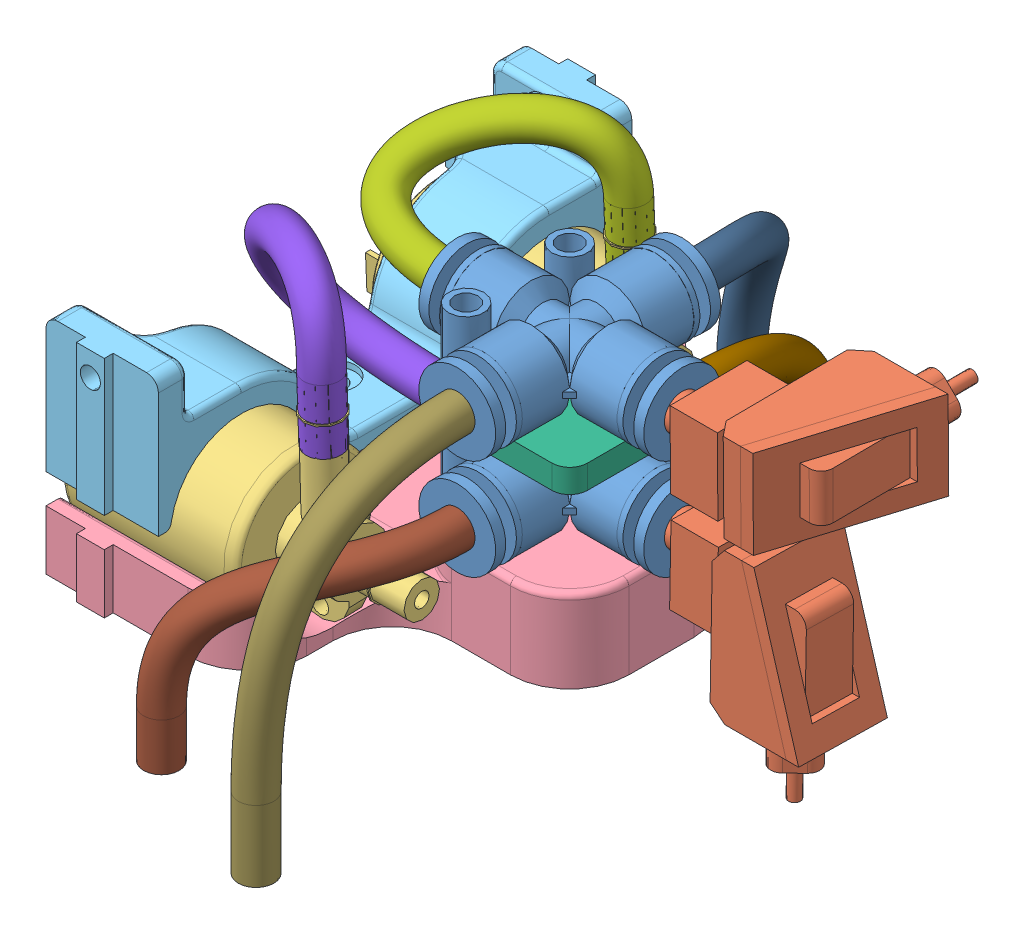
SolidWorks assembly Pneumatique, configuration Défaut. Lengths in mm.
Overall size (98.5 73.06 104.94).
15 component instances, 12 part files, 50 mates.
Components (placement in the parent):
- CroixPiquageRapideD06-1: CroixPiquageRapideD06 [Default] at (39.5 20.5 0) x (0 0 1) z (0 -1 0) size (38 38 13)
- CapteurVide_CKD_PPE-V01A-H6-B-1: CapteurVide_CKD_PPE-V01A-H6-B [Défaut] at (63 20.5 0) x (0 -0.999843 0.017733) z (0 0.017733 0.999843) size (37 43 15)
- Electrovanne_CylindriqueD24_NC_12V-1: Electrovanne_CylindriqueD24_NC_12V [Default] at (-8.5 14 26) x (0 0.999367 0.035582) z (0 0.035582 -0.999367) size (38.24 53 24.48)
- Electrovanne_CylindriqueD24_NC_12V-2: Electrovanne_CylindriqueD24_NC_12V [Default] at (-8.5 14 -26) x (0 0.999176 0.040592) z (0 0.040592 -0.999176) size (38.24 53 24.48)
- CroixPiquageRapideD06-2: CroixPiquageRapideD06 [Default] at (39.5 37.5 0) x (0 0 1) z (0 -1 0) size (38 38 13)
- CapteurVide_CKD_PPE-V01A-H6-B-2: CapteurVide_CKD_PPE-V01A-H6-B [Défaut] at (63 37.5 0) x (0 0.007638 -0.999971) z (0 -0.999971 -0.007638) size (37 43 15)
- Pneumatique_Support-1: Pneumatique_Support [Défaut] at origin size (64.23 14 83)
- Pneumatique_Top-1: Pneumatique_Top [Défaut] at (0 15 0) size (19.23 27.5 83)
- Pneumatique_Entretoise-1: Pneumatique_Entretoise [Défaut] at (39.5 27 0) size (24 4 24)
- tuyau1^Pneumatique-1: tuyau1^Pneumatique [Défaut] at (20.5 37.5 0) x (0 0 1) z (-1 0 0) size (31.4 24.42 35.33) (virtual)
- tuyau2^Pneumatique-1: tuyau2^Pneumatique [Défaut] at (20.5 20.5 0) x (0 0 1) z (-1 0 0) size (33.54 37.08 42) (virtual)
- tuyau3^Pneumatique-1: tuyau3^Pneumatique [Défaut] at (39.5 20.5 -19) x (0 -1 0) z (0 0 -1) size (42.15 12.06 47.59) (virtual)
- tuyau4^Pneumatique-1: tuyau4^Pneumatique [Défaut] at (39.5 37.5 -19) x (0 -1 0) z (0 0 -1) size (49.1 26.51 49.11) (virtual)
- tuyau5^Pneumatique-1: tuyau5^Pneumatique [Défaut] at (39.5 20.5 19) x (0 1 0) z (0 0 1) size (32.28 26.54 48.84) (virtual)
- tuyau6^Pneumatique-1: tuyau6^Pneumatique [Défaut] at (39.5 37.5 19) x (0 1 0) z (0 0 1) size (59 12.1 47.35) (virtual)
Mates (geometry in assembly coordinates):
- Coïncidente420: coincident: plane of assembly; plane of assembly; plane of CroixPiquageRapideD06-1 through (30.75 14 -8.75) normal (0 -1 0); plane of Pneumatique_Support-1 through (0 14 0) normal (0 1 0)
- Coaxiale167: concentric: cylinder of assembly; cylinder of assembly; cylinder of CroixPiquageRapideD06-1 through (30.75 14 -8.75) axis (0 1 0) radius 2; cylinder of Pneumatique_Support-1 through (30.75 14 -8.75) axis (0 1 0) radius 1.7
- Coaxiale168: concentric: cylinder of assembly; cylinder of assembly; cylinder of CroixPiquageRapideD06-1 through (30.75 14 8.75) axis (0 1 0) radius 3; cylinder of Pneumatique_Support-1 through (30.75 14 8.75) axis (0 1 0) radius 1.7
- Coaxiale169: concentric: cylinder of assembly; cylinder of assembly; cylinder of CroixPiquageRapideD06-1 through (30.75 14 -8.75) axis (0 1 0) radius 2; cylinder of CroixPiquageRapideD06-2 through (30.75 31 -8.75) axis (0 1 0) radius 2
- Coaxiale170: concentric: cylinder of assembly; cylinder of assembly; cylinder of CroixPiquageRapideD06-1 through (30.75 14 8.75) axis (0 1 0) radius 2; cylinder of CroixPiquageRapideD06-2 through (30.75 31 8.75) axis (0 1 0) radius 2
- Distance58: distance = 17 mm: plane of assembly; plane of assembly; plane of CroixPiquageRapideD06-2 through (30.75 44 -8.75) normal (0 1 0); plane of CroixPiquageRapideD06-1 through (30.75 27 -8.75) normal (0 1 0)
- Coaxiale171: concentric: cylinder of assembly; cylinder of assembly; cylinder of CroixPiquageRapideD06-1 through (39.5 20.5 0) axis (-1 0 0) radius 3; cylinder of CapteurVide_CKD_PPE-V01A-H6-B-1 through (43 20.5 0) axis (1 0 0) radius 3
- Coïncidente422: coincident: plane of assembly; plane of assembly; plane of CroixPiquageRapideD06-1 through (43 20.5 1.5) normal (1 0 0); plane of CapteurVide_CKD_PPE-V01A-H6-B-1 through (43 20.5 0) normal (-1 0 0)
- Coaxiale174: concentric: cylinder of assembly; cylinder of assembly; cylinder of CroixPiquageRapideD06-1 through (30.75 14 -8.75) axis (0 1 0) radius 2; cylinder of Pneumatique_Entretoise-1 through (30.75 31 -8.75) axis (0 1 0) radius 1.7
- Coaxiale175: concentric: cylinder of assembly; cylinder of assembly; cylinder of CroixPiquageRapideD06-1 through (30.75 14 8.75) axis (0 1 0) radius 3; cylinder of Pneumatique_Entretoise-1 through (30.75 31 8.75) axis (0 1 0) radius 1.7
- Coïncidente426: coincident: plane of assembly; plane of assembly; plane of CroixPiquageRapideD06-1 through (30.75 27 -8.75) normal (0 1 0); plane of Pneumatique_Entretoise-1 through (39.5 27 0) normal (0 -1 0)
- Coïncidente419: coincident: plane of assembly; plane of assembly; plane of Pneumatique_Support-1 through (-9 10 -40) normal (-1 0 0); plane of Electrovanne_CylindriqueD24_NC_12V-1 through (-9 14 26) normal (-1 0 0)
- Coaxiale166: concentric: cylinder of assembly; cylinder of assembly; cylinder of Electrovanne_CylindriqueD24_NC_12V-1 through (-8.5 14 26) axis (1 0 0) radius 12; cylinder of Pneumatique_Support-1 through (58.9411 14 26) axis (-1 0 0) radius 12
- Coïncidente418: coincident: plane of assembly; plane of assembly; plane of Pneumatique_Support-1 through (-9 10 -40) normal (-1 0 0); plane of Electrovanne_CylindriqueD24_NC_12V-2 through (-9 14 -26) normal (-1 0 0)
- Coaxiale165: concentric: cylinder of assembly; cylinder of assembly; cylinder of Electrovanne_CylindriqueD24_NC_12V-2 through (-8.5 14 -26) axis (1 0 0) radius 12; cylinder of Pneumatique_Support-1 through (58.9411 14 -26) axis (-1 0 0) radius 12
- Coaxiale173: concentric: cylinder of assembly; cylinder of assembly; cylinder of Electrovanne_CylindriqueD24_NC_12V-2 through (-8.5 14 -26) axis (1 0 0) radius 12; cylinder of Pneumatique_Top-1 through (43.9411 14 -26) axis (-1 0 0) radius 12
- Coïncidente423: coincident: plane of assembly; plane of assembly; plane of CroixPiquageRapideD06-2 through (43 37.5 1.5) normal (1 0 0); plane of CapteurVide_CKD_PPE-V01A-H6-B-2 through (43 37.5 0) normal (-1 0 0)
- Coaxiale172: concentric: cylinder of CroixPiquageRapideD06-2 through (39.5 37.5 0) axis (-1 0 0) radius 3; cylinder of CapteurVide_CKD_PPE-V01A-H6-B-2 through (43 37.5 0) axis (1 0 0) radius 3
- Coïncidente425: coincident: plane of Pneumatique_Support-1 through (-9 10 -40) normal (-1 0 0); plane of Pneumatique_Top-1 through (-9 30 -40) normal (-1 0 0)
- Sur place1: in place: plane of ? through (-62.0814 101.8405 -29.0146) normal (0 0.999176 0.040592); plane of ? through (0 100.4958 4.0827) normal (0 0.999176 0.040592); moOrthogonalPlaneRef_w of ? through (-62.0814 101.8405 -29.0146) normal (0 0.999176 0.040592); plane of ? through (0 100.4958 4.0827) normal (0 0.040592 -0.999176); plane of ? through (-62.0814 101.8405 -29.0146) normal (0 0.999176 0.040592); plane of ? through (0 100.4958 4.0827) normal (1 0 0); plane of ? through (-62.0814 101.8405 -29.0146) normal (0 0.999176 0.040592); unknown of ?
- Coïncidente427: coincident: plane of assembly; plane of assembly; plane of Electrovanne_CylindriqueD24_NC_12V-2; plane of ?
- Coïncidente428: coincident: plane of ? through (-98.0814 101.8405 -29.0146) normal (1 0 0); plane of ? through (-98.0814 101.8405 -29.0146) normal (1 0 0)
- Coïncidente429: coincident: plane of ? through (-98.0814 101.8405 -29.0146) normal (0 0.040592 -0.999176); plane of ? through (-98.0814 101.8405 -29.0146) normal (0 -0.040592 0.999176)
- Sur place2: in place: plane of ? through (-69.0814 99.3619 -10.57) normal (-1 0 0); plane of ? through (-69.0814 0 0) normal (-1 0 0); plane of ? through (-69.0814 99.3619 -10.57) normal (-1 0 0); plane of ? through (-69.0814 0 0) normal (0 1 0); plane of ? through (-69.0814 99.3619 -10.57) normal (-1 0 0); plane of ? through (-69.0814 0 0) normal (0 0 1); plane of CroixPiquageRapideD06-2 through (20.5 37.5 -6.5) normal (-1 0 0); unknown of tuyau1^Pneumatique-1
- Coïncidente430: coincident: plane of assembly; plane of assembly; plane of CroixPiquageRapideD06-2; plane of tuyau1^Pneumatique-1
- Coïncidente431: coincident: plane of assembly; plane of assembly; moOrthogonalPlaneRef_w of CroixPiquageRapideD06-2 through (20.5 37.5 0) normal (0 1 0); plane of tuyau1^Pneumatique-1 through (20.5 37.5 0) normal (0 1 0)
- Coïncidente432: coincident: plane of assembly; plane of assembly; moOrthogonalPlaneRef_w of CroixPiquageRapideD06-2 through (20.5 37.5 0) normal (0 0 -1); plane of tuyau1^Pneumatique-1 through (20.5 37.5 0) normal (0 0 1)
- Sur place3: in place: plane of ? through (-69.0814 82.3619 -10.57) normal (-1 0 0); plane of ? through (-69.0814 0 0) normal (-1 0 0); plane of ? through (-69.0814 82.3619 -10.57) normal (-1 0 0); plane of ? through (-69.0814 0 0) normal (0 1 0); plane of ? through (-69.0814 82.3619 -10.57) normal (-1 0 0); plane of ? through (-69.0814 0 0) normal (0 0 1); plane of CroixPiquageRapideD06-1 through (20.5 20.5 -6.5) normal (-1 0 0); unknown of tuyau2^Pneumatique-1
- Coïncidente433: coincident: plane of assembly; plane of assembly; plane of CroixPiquageRapideD06-1; plane of tuyau2^Pneumatique-1
- Coïncidente434: coincident: plane of assembly; plane of assembly; moOrthogonalPlaneRef_w of CroixPiquageRapideD06-1 through (20.5 20.5 0) normal (0 1 0); plane of tuyau2^Pneumatique-1 through (20.5 20.5 0) normal (0 1 0)
- Coïncidente435: coincident: plane of assembly; plane of assembly; moOrthogonalPlaneRef_w of CroixPiquageRapideD06-1 through (20.5 20.5 0) normal (0 0 -1); plane of tuyau2^Pneumatique-1 through (20.5 20.5 0) normal (0 0 1)
- Coïncidente436: coincident: plane of assembly through (0 0 0) normal (0 0 1); plane of Pneumatique_Support-1 through (0 0 0) normal (0 0 1); plane of assembly
- Coïncidente437: coincident: plane of assembly through (0 0 0) normal (1 0 0); plane of Pneumatique_Support-1 through (0 0 0) normal (1 0 0); plane of assembly
- Coïncidente438: coincident: plane of assembly through (0 0 0) normal (0 1 0); plane of Pneumatique_Support-1 through (0 0 0) normal (0 1 0); plane of assembly
- Sur place4: in place: plane of CroixPiquageRapideD06-1 through (46 20.5 -19) normal (0 0 -1); plane of ? through (0 0 -19) normal (0 0 -1); plane of CroixPiquageRapideD06-1 through (46 20.5 -19) normal (0 0 -1); plane of ? through (0 0 -19) normal (0 1 0); plane of CroixPiquageRapideD06-1 through (46 20.5 -19) normal (0 0 -1); plane of ? through (0 0 -19) normal (-1 0 0); plane of CroixPiquageRapideD06-1 through (46 20.5 -19) normal (0 0 -1); unknown of tuyau3^Pneumatique-1
- Coïncidente439: coincident: plane of assembly; plane of assembly; plane of CroixPiquageRapideD06-1; plane of tuyau3^Pneumatique-1
- Coïncidente440: coincident: plane of assembly; plane of assembly; moOrthogonalPlaneRef_w of CroixPiquageRapideD06-1 through (39.5 20.5 -19) normal (-1 0 0); plane of tuyau3^Pneumatique-1 through (39.5 20.5 -19) normal (-1 0 0)
- Coïncidente441: coincident: plane of assembly; plane of assembly; moOrthogonalPlaneRef_w of CroixPiquageRapideD06-1 through (39.5 20.5 -19) normal (0 1 0); plane of tuyau3^Pneumatique-1 through (39.5 20.5 -19) normal (0 -1 0)
- Sur place5: in place: plane of CroixPiquageRapideD06-2 through (46 37.5 -19) normal (0 0 -1); plane of ? through (0 0 -19) normal (0 0 -1); plane of CroixPiquageRapideD06-2 through (46 37.5 -19) normal (0 0 -1); plane of ? through (0 0 -19) normal (0 1 0); plane of CroixPiquageRapideD06-2 through (46 37.5 -19) normal (0 0 -1); plane of ? through (0 0 -19) normal (-1 0 0); plane of CroixPiquageRapideD06-2 through (46 37.5 -19) normal (0 0 -1); unknown of tuyau4^Pneumatique-1
- Coïncidente442: coincident: plane of assembly; plane of assembly; plane of CroixPiquageRapideD06-2; plane of tuyau4^Pneumatique-1
- Coïncidente443: coincident: plane of assembly; plane of assembly; moOrthogonalPlaneRef_w of CroixPiquageRapideD06-2 through (39.5 37.5 -19) normal (-1 0 0); plane of tuyau4^Pneumatique-1 through (39.5 37.5 -19) normal (-1 0 0)
- Coïncidente444: coincident: plane of assembly; plane of assembly; moOrthogonalPlaneRef_w of CroixPiquageRapideD06-2 through (39.5 37.5 -19) normal (0 1 0); plane of tuyau4^Pneumatique-1 through (39.5 37.5 -19) normal (0 -1 0)
- Sur place6: in place: plane of CroixPiquageRapideD06-1 through (33 20.5 19) normal (0 0 1); plane of ? through (0 0 19) normal (0 0 1); plane of CroixPiquageRapideD06-1 through (33 20.5 19) normal (0 0 1); plane of ? through (0 0 19) normal (0 1 0); plane of CroixPiquageRapideD06-1 through (33 20.5 19) normal (0 0 1); plane of ? through (0 0 19) normal (1 0 0); plane of CroixPiquageRapideD06-1 through (33 20.5 19) normal (0 0 1); unknown of tuyau5^Pneumatique-1
- Coïncidente445: coincident: plane of assembly; plane of assembly; plane of CroixPiquageRapideD06-1; plane of tuyau5^Pneumatique-1
- Coïncidente446: coincident: plane of assembly; plane of assembly; moOrthogonalPlaneRef_w of CroixPiquageRapideD06-1 through (39.5 20.5 19) normal (-1 0 0); plane of tuyau5^Pneumatique-1 through (39.5 20.5 19) normal (-1 0 0)
- Coïncidente447: coincident: plane of assembly; plane of assembly; moOrthogonalPlaneRef_w of CroixPiquageRapideD06-1 through (39.5 20.5 19) normal (0 -1 0); plane of tuyau5^Pneumatique-1 through (39.5 20.5 19) normal (0 1 0)
- Sur place7: in place: plane of CroixPiquageRapideD06-2 through (33 37.5 19) normal (0 0 1); plane of ? through (0 0 19) normal (0 0 1); plane of CroixPiquageRapideD06-2 through (33 37.5 19) normal (0 0 1); plane of ? through (0 0 19) normal (0 1 0); plane of CroixPiquageRapideD06-2 through (33 37.5 19) normal (0 0 1); plane of ? through (0 0 19) normal (1 0 0); plane of CroixPiquageRapideD06-2 through (33 37.5 19) normal (0 0 1); unknown of tuyau6^Pneumatique-1
- Coïncidente448: coincident: plane of assembly; plane of assembly; plane of CroixPiquageRapideD06-2; plane of tuyau6^Pneumatique-1
- Coïncidente449: coincident: plane of assembly; plane of assembly; moOrthogonalPlaneRef_w of CroixPiquageRapideD06-2 through (39.5 37.5 19) normal (-1 0 0); plane of tuyau6^Pneumatique-1 through (39.5 37.5 19) normal (-1 0 0)
- Coïncidente450: coincident: plane of assembly; plane of assembly; moOrthogonalPlaneRef_w of CroixPiquageRapideD06-2 through (39.5 37.5 19) normal (0 -1 0); plane of tuyau6^Pneumatique-1 through (39.5 37.5 19) normal (0 1 0)
